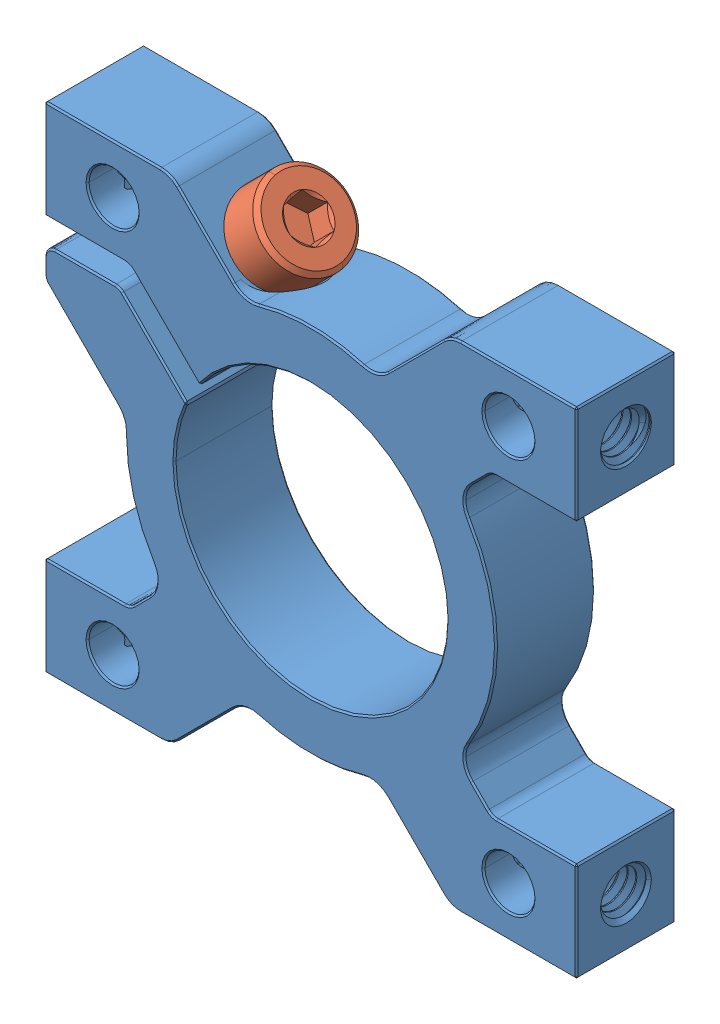
SolidWorks assembly 2-Side, 2-Post Clamping Mount (43mm Width, 22mm Bore)1401-0043-0022, configuration Default. Lengths in mm.
Overall size (43 41.32 8.01).
2 component instances, 2 part files, 0 mates.
Components (placement in the parent):
- 1401-0043-0022.STEP-1: 1401-0043-0022.STEP [Default] at (-62.2409 15.0933 22.5895) size (43 40 8)
- 2800-0004-0016_90128A207.STEP-1: 2800-0004-0016_90128A207.STEP [Default] at (-80.5252 19.4364 22.5895) x (0.698322 -0.698322 -0.157143) z (-0.707107 -0.707107 0) size (7 7 20.01)
